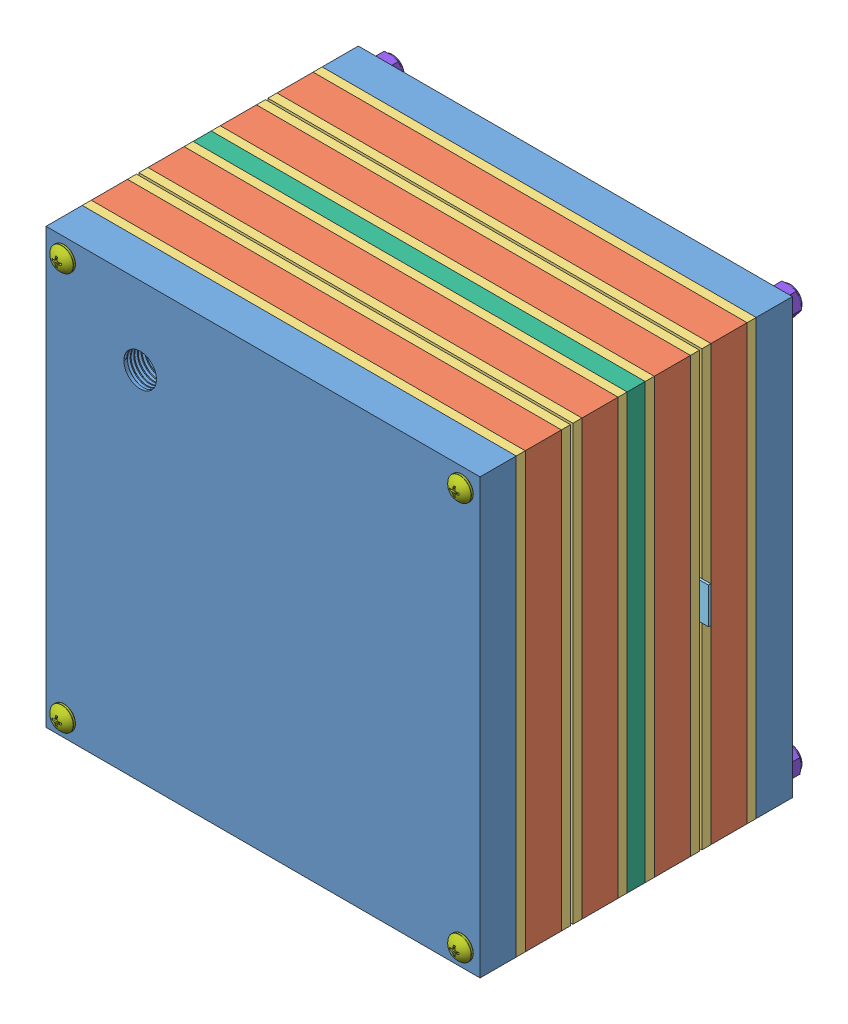
SolidWorks assembly SaltBox, configuration Default. Lengths in mm.
Overall size (158.75 152.4 118.48).
31 component instances, 8 part files, 24 mates.
Components (placement in the parent):
- Meshwitch-1: Meshwitch [Default] at (210.6512 39.7669 62.8556) size (155.58 152.4 51.67)
  - Walls-1: Walls [Default] at (-141.74 -79.9092 -25.0724) size (152.4 152.4 13.2)
  - Space-1: Space [Default] at (-105.4085 -132.7748 -9.1974) size (152.4 152.4 12.7)
  - Space-3: Space [Default] at (-105.4085 -132.7748 10.7034) size (152.4 152.4 12.7)
  - RubberGasket-1: RubberGasket [Default] at (-128.6825 -93.4547 -12.3724) size (152.4 152.4 3.17)
  - RubberGasket-2: RubberGasket [Default] at (-128.6825 -93.4547 3.5026) size (152.4 152.4 3.17)
  - RubberGasket-3: RubberGasket [Default] at (-128.6825 -93.4547 7.5284) size (152.4 152.4 3.17)
  - MeshBus-1: MeshBus [Default] at (-103.2743 -75.166 -8.8922) x (0 1 0) z (1 0 0) size (146.05 0.85 152.4)
    - 9225T321_Acid-Resistant 400 Nickel Wire Cloth-1: 9225T321_Acid-Resistant 400 Nickel Wire Cloth [9225T321] at (-50.5853 15.5951 16.0981) size (146.05 0.05 146.05)
    - CopperBus-1: CopperBus [Default] at (-63.3029 16.4205 -1.338) x (1 0 0) z (0 0 -1) size (146.05 0.8 152.4)
  - RubberGasket-4: RubberGasket [Default] at (-128.6825 -93.4547 23.4034) size (152.4 152.4 3.17)
- Meshwitch-2: Meshwitch [Default] at (29.9488 39.7669 122.3624) x (-1 0 0) z (0 0 -1) size (155.58 152.4 51.67)
  - Walls-1: Walls [Default] at (-141.74 -79.9092 -25.0724) size (152.4 152.4 13.2)
  - Space-1: Space [Default] at (-105.4085 -132.7748 -9.1974) size (152.4 152.4 12.7)
  - Space-3: Space [Default] at (-105.4085 -132.7748 10.7034) size (152.4 152.4 12.7)
  - RubberGasket-1: RubberGasket [Default] at (-128.6825 -93.4547 -12.3724) size (152.4 152.4 3.17)
  - RubberGasket-2: RubberGasket [Default] at (-128.6825 -93.4547 3.5026) size (152.4 152.4 3.17)
  - RubberGasket-3: RubberGasket [Default] at (-128.6825 -93.4547 7.5284) size (152.4 152.4 3.17)
  - MeshBus-1: MeshBus [Default] at (-103.2743 -75.166 -8.8922) x (0 1 0) z (1 0 0) size (146.05 0.85 152.4)
    - 9225T321_Acid-Resistant 400 Nickel Wire Cloth-1: 9225T321_Acid-Resistant 400 Nickel Wire Cloth [9225T321] at (-50.5853 15.5951 16.0981) size (146.05 0.05 146.05)
    - CopperBus-1: CopperBus [Default] at (-63.3029 16.4205 -1.338) x (1 0 0) z (0 0 -1) size (146.05 0.8 152.4)
  - RubberGasket-4: RubberGasket [Default] at (-128.6825 -93.4547 23.4034) size (152.4 152.4 3.17)
- Stalagtight-2: Stalagtight [Default] at (360.4747 -248.8109 89.434) size (152.4 152.4 6.35)
- 90272A363_Zinc-Plated Steel Pan Head Phillips Screw-1: 90272A363_Zinc-Plated Steel Pan Head Phillips Screw [90272A363] at (50.45 -19.3095 88.5703) size (8.18 8.18 124.22)
- 90272A363_Zinc-Plated Steel Pan Head Phillips Screw-2: 90272A363_Zinc-Plated Steel Pan Head Phillips Screw [90272A363] at (190.15 -19.3095 88.5703) size (8.18 8.18 124.22)
- 90272A363_Zinc-Plated Steel Pan Head Phillips Screw-3: 90272A363_Zinc-Plated Steel Pan Head Phillips Screw [90272A363] at (50.45 -159.0095 88.5703) size (8.18 8.18 124.22)
- 90272A363_Zinc-Plated Steel Pan Head Phillips Screw-4: 90272A363_Zinc-Plated Steel Pan Head Phillips Screw [90272A363] at (190.15 -159.0095 88.5703) size (8.18 8.18 124.22)
- 90631A009_Low-Strength Steel Nylon-Insert Locknut-1: 90631A009_Low-Strength Steel Nylon-Insert Locknut [90631A009] at (190.15 -159.0095 37.7832) x (1 0 0) z (0 1 0) size (8.73 6.09 10.08)
- 90631A009_Low-Strength Steel Nylon-Insert Locknut-2: 90631A009_Low-Strength Steel Nylon-Insert Locknut [90631A009] at (50.45 -159.0095 37.7832) x (-0.923728 -0.383049 0) z (0.383049 -0.923728 0) size (8.73 6.09 10.08)
- 90631A009_Low-Strength Steel Nylon-Insert Locknut-3: 90631A009_Low-Strength Steel Nylon-Insert Locknut [90631A009] at (190.15 -19.3095 37.7832) x (-0.923728 -0.383049 0) z (0.383049 -0.923728 0) size (8.73 6.09 10.08)
- 90631A009_Low-Strength Steel Nylon-Insert Locknut-4: 90631A009_Low-Strength Steel Nylon-Insert Locknut [90631A009] at (50.45 -19.3095 37.7832) x (-0.923728 -0.383049 0) z (0.383049 -0.923728 0) size (8.73 6.09 10.08)
Mates (geometry in assembly coordinates):
- Parallel1: parallel aligned: plane of Meshwitch-1/Space-1 through (44.1 -165.3595 66.3582) normal (0 -1 0); plane of Meshwitch-2/Walls-1 through (196.5 -165.3595 134.7348) normal (0 -1 0)
- Coincident6: coincident aligned: plane of Meshwitch-1/Space-1 through (196.5 -12.9595 66.3582) normal (1 0 0); plane of Meshwitch-2/Walls-1 through (196.5 -12.9595 134.7348) normal (1 0 0)
- Coincident11: coincident aligned: plane of Meshwitch-2/Space-3 through (44.1 -12.9595 98.959) normal (-1 0 0); plane of Stalagtight-2 through (44.1 -248.8109 95.784) normal (-1 0 0)
- Coincident12: coincident aligned: plane of Meshwitch-1/Space-3 through (44.1 -12.9595 86.259) normal (-1 0 0); plane of Stalagtight-2 through (44.1 -248.8109 95.784) normal (-1 0 0)
- Coincident13: coincident aligned: plane of Meshwitch-1/Space-3 through (44.1 -12.9595 86.259) normal (0 1 0); plane of Stalagtight-2 through (360.4747 -12.9595 95.784) normal (0 1 0)
- Coincident14: coincident aligned: plane of Meshwitch-2/Space-3 through (196.5 -12.9595 98.959) normal (0 1 0); plane of Stalagtight-2 through (360.4747 -12.9595 95.784) normal (0 1 0)
- Concentric11: concentric aligned: cylinder of Meshwitch-2/Walls-1 through (50.45 -19.3095 147.4348) axis (0 0 1) radius 2.2479; cylinder of 90272A363_Zinc-Plated Steel Pan Head Phillips Screw-1 through (50.45 -19.3095 150.3558) axis (0 0 1) radius 2.0828
- Coincident151: coincident anti-aligned: plane of Meshwitch-2/Walls-1 through (171.6888 -40.1423 147.4348) normal (0 0 1); plane of 90272A363_Zinc-Plated Steel Pan Head Phillips Screw-1 through (54.3307 -19.3095 147.4348) normal (0 0 -1)
- Concentric21: concentric aligned: cylinder of Meshwitch-2/Walls-1 through (190.15 -19.3095 147.4348) axis (0 0 1) radius 2.2479; cylinder of 90272A363_Zinc-Plated Steel Pan Head Phillips Screw-2 through (190.15 -19.3095 150.3558) axis (0 0 1) radius 2.0828
- Coincident161: coincident anti-aligned: plane of Meshwitch-2/Walls-1 through (171.6888 -40.1423 147.4348) normal (0 0 1); plane of 90272A363_Zinc-Plated Steel Pan Head Phillips Screw-2 through (194.0307 -19.3095 147.4348) normal (0 0 -1)
- Concentric31: concentric aligned: cylinder of Meshwitch-2/Walls-1 through (50.45 -159.0095 147.4348) axis (0 0 1) radius 2.2479; cylinder of 90272A363_Zinc-Plated Steel Pan Head Phillips Screw-3 through (50.45 -159.0095 150.3558) axis (0 0 1) radius 2.0828
- Coincident171: coincident anti-aligned: plane of Meshwitch-2/Walls-1 through (171.6888 -40.1423 147.4348) normal (0 0 1); plane of 90272A363_Zinc-Plated Steel Pan Head Phillips Screw-3 through (54.3307 -159.0095 147.4348) normal (0 0 -1)
- Concentric41: concentric aligned: cylinder of Meshwitch-2/Walls-1 through (190.15 -159.0095 147.4348) axis (0 0 1) radius 2.2479; cylinder of 90272A363_Zinc-Plated Steel Pan Head Phillips Screw-4 through (190.15 -159.0095 150.3558) axis (0 0 1) radius 2.0828
- Coincident181: coincident anti-aligned: plane of Meshwitch-2/Walls-1 through (171.6888 -40.1423 147.4348) normal (0 0 1); plane of 90272A363_Zinc-Plated Steel Pan Head Phillips Screw-4 through (194.0307 -159.0095 147.4348) normal (0 0 -1)
- Coincident19: coincident anti-aligned: plane of Meshwitch-1/Walls-1 through (68.9111 -40.1423 37.7832) normal (0 0 -1); plane of 90631A009_Low-Strength Steel Nylon-Insert Locknut-1 through (185.7843 -166.5709 37.7832) normal (0 0 1)
- Concentric5: concentric anti-aligned: circle of Meshwitch-1/Walls-1; circle of 90631A009_Low-Strength Steel Nylon-Insert Locknut-1
- Coincident20: coincident anti-aligned: plane of Meshwitch-1/Walls-1 through (68.9111 -40.1423 37.7832) normal (0 0 -1); plane of 90631A009_Low-Strength Steel Nylon-Insert Locknut-2 through (51.5862 -150.3525 37.7832) normal (0 0 1)
- Concentric6: concentric aligned: circle of Meshwitch-1/Walls-1; circle of 90631A009_Low-Strength Steel Nylon-Insert Locknut-2
- Coincident21: coincident anti-aligned: plane of Meshwitch-1/Walls-1 through (68.9111 -40.1423 37.7832) normal (0 0 -1); plane of 90631A009_Low-Strength Steel Nylon-Insert Locknut-4 through (51.5862 -10.6525 37.7832) normal (0 0 1)
- Coincident22: coincident anti-aligned: plane of Meshwitch-1/Walls-1 through (68.9111 -40.1423 37.7832) normal (0 0 -1); plane of 90631A009_Low-Strength Steel Nylon-Insert Locknut-3 through (191.2862 -10.6525 37.7832) normal (0 0 1)
- Concentric8: concentric aligned: cylinder of Meshwitch-1/Walls-1 through (190.15 -19.3095 147.4348) axis (0 0 1) radius 2.2479; cylinder of 90631A009_Low-Strength Steel Nylon-Insert Locknut-3 through (190.15 -19.3095 32.746) axis (0 0 1) radius 1.7258
- Concentric9: concentric aligned: cylinder of Meshwitch-1/Walls-1 through (50.45 -19.3095 147.4348) axis (0 0 1) radius 2.2479; circle of 90631A009_Low-Strength Steel Nylon-Insert Locknut-4
- Coincident183: coincident anti-aligned: plane of Meshwitch-1/RubberGasket-4 through (81.9687 -53.6878 89.434) normal (0 0 1); plane of Stalagtight-2 through (360.4747 -248.8109 89.434) normal (0 0 -1)
- Coincident184: coincident anti-aligned: plane of Meshwitch-2/RubberGasket-4 through (158.6313 -53.6878 95.784) normal (0 0 -1); plane of Stalagtight-2 through (360.4747 -248.8109 95.784) normal (0 0 1)
